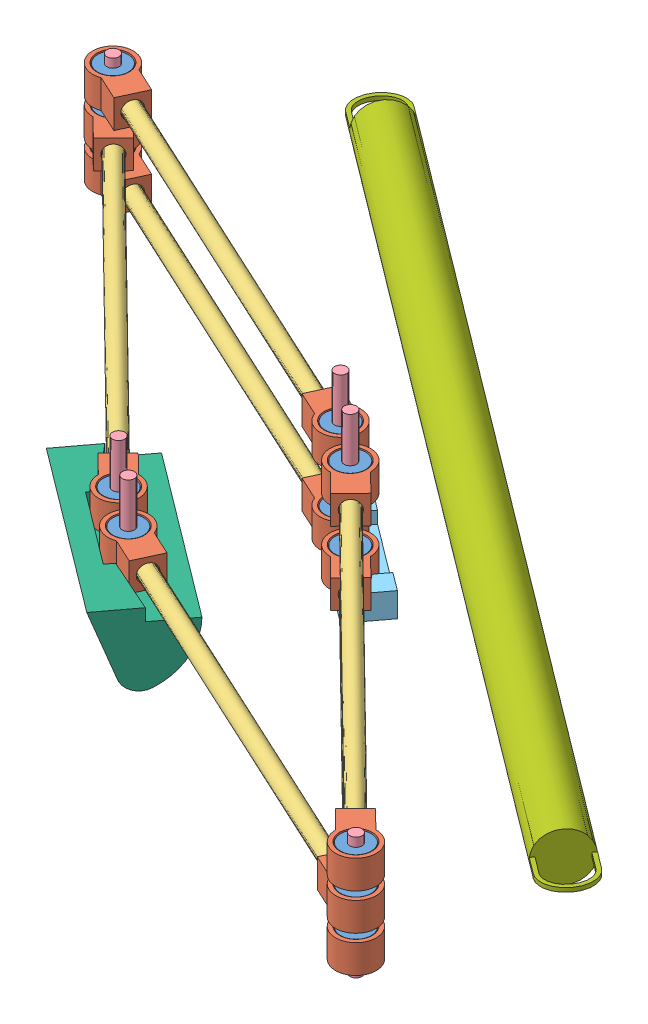
SolidWorks assembly leg_assembly1, configuration Default. Lengths in mm.
Overall size (234.39 41.67 185.98).
39 component instances, 7 part files, 94 mates.
Components (placement in the parent):
- bushing-3: bushing [Default] at (-50.3591 2.1821 -25.7812) x (0.792479 0 -0.609899) z (0.609899 0 0.792479) size (7.5 5 7.5)
- LegConnector1-3: LegConnector1 [Default] at (-50.3591 -3.9179 -25.7812) x (0.420255 0 -0.907406) z (0.907406 0 0.420255) size (10 7 15)
- bushing-4: bushing [Default] at (53.9926 2.1821 22.5482) size (7.5 5 7.5)
- LegCarbon-2: LegCarbon [Default] at (-45.8221 -0.4179 -23.6799) x (0.346449 0.566041 -0.748044) z (0.237882 -0.824377 -0.513629) size (4 105 4)
- LegConnector1-4: LegConnector1 [Default] at (53.9926 -3.9179 22.5482) x (-0.420255 0 0.907406) z (-0.907406 0 -0.420255) size (10 7 15)
- bushing-5: bushing [Default] at (-28.0167 11.1821 -58.0712) x (0.792479 0 -0.609899) z (0.609899 0 0.792479) size (7.5 5 7.5)
- LegConnector1-5: LegConnector1 [Default] at (-28.0167 5.0821 -58.0712) x (0.701038 0 -0.713124) z (0.713124 0 0.701038) size (10 7 15)
- bushing-6: bushing [Default] at (53.9926 11.1821 22.5482) size (7.5 5 7.5)
- LegCarbon-3: LegCarbon [Default] at (-24.4511 8.5821 -54.566) x (-0.676998 -0.259628 0.68867) z (-0.182009 0.965709 0.185147) size (4 105 4)
- LegConnector1-6: LegConnector1 [Default] at (53.9926 5.0821 22.5482) x (-0.701038 0 0.713124) z (-0.713124 0 -0.701038) size (10 7 15)
- bushing-7: bushing [Default] at (-28.0167 -6.8179 -58.0712) x (0.792479 0 -0.609899) z (0.609899 0 0.792479) size (7.5 5 7.5)
- LegConnector1-7: LegConnector1 [Default] at (-28.0167 -12.9179 -58.0712) x (0.701038 0 -0.713124) z (0.713124 0 0.701038) size (10 7 15)
- bushing-8: bushing [Default] at (53.9926 -6.8179 22.5482) size (7.5 5 7.5)
- LegCarbon-4: LegCarbon [Default] at (-24.4511 -9.4179 -54.566) x (0.513161 -0.681303 -0.522008) z (-0.477619 -0.732001 0.485854) size (4 105 4)
- LegConnector1-8: LegConnector1 [Default] at (53.9926 -12.9179 22.5482) x (-0.701038 0 0.713124) z (-0.713124 0 -0.701038) size (10 7 15)
- bushing-10: bushing [Default] at (-59.954 2.1821 -32.988) size (7.5 5 7.5)
- ScrewThread-1: ScrewThread [Default] at (53.9926 -15.9179 22.5482) x (0.842646 0 0.538468) z (-0.538468 0 0.842646) size (3 30 3)
- LegConnector1-11: LegConnector1 [Default] at (-59.954 -3.9179 -32.988) x (-0.701038 0 0.713124) z (-0.713124 0 -0.701038) size (10 7 15)
- LegCarbon-6: LegCarbon [Default] at (-42.1487 -9.4179 -67.3792) x (-0.307627 -0.681303 0.664222) z (0.286321 -0.732001 -0.618218) size (4 105 4)
- LegConnector1-12: LegConnector1 [Default] at (-141.9633 -12.9179 -113.6073) x (0.420255 0 -0.907406) z (0.907406 0 0.420255) size (10 7 15)
- ScrewThread-2: ScrewThread [Default] at (-141.9633 -15.9179 -113.6073) x (0.842646 0 0.538468) z (-0.538468 0 0.842646) size (3 30 3)
- bushing-11: bushing [Default] at (-141.9633 2.1821 -113.6073) size (7.5 5 7.5)
- LegConnector1-13: LegConnector1 [Default] at (-141.9633 -3.9179 -113.6073) x (0.701038 0 -0.713124) z (0.713124 0 0.701038) size (10 7 15)
- LegCarbon-7: LegCarbon [Default] at (-63.5196 -0.4179 -36.4932) x (-0.577919 0.566041 0.587883) z (-0.396816 -0.824377 0.403658) size (4 105 4)
- bushing-12: bushing [Default] at (-141.9633 -6.8179 -113.6073) size (7.5 5 7.5)
- LegCarbon-8: LegCarbon [Default] at (-42.1487 8.5821 -67.3792) x (0.405844 -0.259628 -0.87629) z (0.10911 0.965709 -0.235588) size (4 105 4)
- LegConnector1-14: LegConnector1 [Default] at (-141.9633 5.0821 -113.6073) x (0.420255 0 -0.907406) z (0.907406 0 0.420255) size (10 7 15)
- LegConnector1-15: LegConnector1 [Default] at (-37.6116 -12.9179 -65.278) x (-0.420255 0 0.907406) z (-0.907406 0 -0.420255) size (10 7 15)
- bushing-13: bushing [Default] at (-37.6116 -6.8179 -65.278) x (0.792479 0 -0.609899) z (0.609899 0 0.792479) size (7.5 5 7.5)
- bushing-14: bushing [Default] at (-141.9633 11.1821 -113.6073) size (7.5 5 7.5)
- bushing-15: bushing [Default] at (-37.6116 11.1821 -65.278) x (0.792479 0 -0.609899) z (0.609899 0 0.792479) size (7.5 5 7.5)
- LegConnector1-16: LegConnector1 [Default] at (-37.6116 5.0821 -65.278) x (-0.420255 0 0.907406) z (-0.907406 0 -0.420255) size (10 7 15)
- Bum2-2: Bum2 [Default] at (-22.6222 -16.1179 -50.2674) x (-0.799576 0 -0.600564) z (0.600564 0 -0.799576) size (30 9 10)
- Foot1-2: Foot1 [Default] at (-77.0435 -19.9118 -41.8724) x (0.600564 0 -0.799576) z (0 -1 0) size (20.25 50 17.67)
- ScrewThread-5: ScrewThread [Default] at (-50.3591 -16.1179 -25.7812) size (3 30 3)
- ScrewThread-6: ScrewThread [Default] at (-59.954 -16.1179 -32.988) size (3 30 3)
- ScrewThread-7: ScrewThread [Default] at (-28.0167 -7.1179 -58.0712) x (0.951589 0 0.307372) z (-0.307372 0 0.951589) size (3 30 3)
- ScrewThread-8: ScrewThread [Default] at (-37.6116 -7.1179 -65.278) size (3 30 3)
- Spring_ext-1: Spring_ext [Default] at (72.2619 1.5513 -10.2483) x (-0.424663 0.707107 0.565386) z (-0.424663 -0.707107 0.565386) size (12 242 12)
Mates (geometry in assembly coordinates):
- Concentric5: concentric anti-aligned: cylinder of bushing-4 through (53.9926 -2.0679 22.5482) axis (0 1 0) radius 2.25; cylinder of LegConnector1-4 through (53.9926 3.0821 22.5482) axis (0 -1 0) radius 2.45
- Concentric6: concentric anti-aligned: cylinder of bushing-3 through (-50.3591 -2.0679 -25.7812) axis (0 1 0) radius 2.25; cylinder of LegConnector1-3 through (-50.3591 3.0821 -25.7812) axis (0 -1 0) radius 2.45
- Concentric7: concentric anti-aligned: cylinder of LegCarbon-2 through (49.4555 -0.4179 20.4469) axis (-0.907406 0 -0.420255) radius 2; cylinder of LegConnector1-4 through (44.9185 -0.4179 18.3456) axis (0.907406 0 0.420255) radius 2.2
- Coincident7: coincident anti-aligned: plane of bushing-3 through (-50.3591 2.1821 -25.7812) normal (0 -1 0); plane of LegConnector1-3 through (-50.3591 2.1821 -25.7812) normal (0 1 0)
- Coincident8: coincident anti-aligned: plane of LegCarbon-2 through (49.4555 -0.4179 20.4469) normal (0.907406 0 0.420255); plane of LegConnector1-4 through (49.4555 -3.9179 20.4469) normal (-0.907406 0 -0.420255)
- Coincident9: coincident anti-aligned: plane of bushing-4 through (53.9926 2.1821 22.5482) normal (0 -1 0); plane of LegConnector1-4 through (53.9926 2.1821 22.5482) normal (0 1 0)
- Coincident10: coincident anti-aligned: plane of LegConnector1-3 through (-45.8221 -3.9179 -23.6799) normal (0.907406 0 0.420255); plane of LegCarbon-2 through (-45.8221 -0.4179 -23.6799) normal (-0.907406 0 -0.420255)
- Parallel3: parallel aligned: plane of LegConnector1-3 through (-45.7123 -3.9179 -27.4862) normal (0.420255 0 -0.907406); plane of LegConnector1-4 through (52.2875 -3.9179 17.9013) normal (0.420255 0 -0.907406)
- Parallel4: parallel aligned: plane of LegConnector1-3 through (-50.3591 3.0821 -25.7812) normal (0 1 0); plane of LegConnector1-4 through (53.9926 3.0821 22.5482) normal (0 1 0)
- Concentric8: concentric aligned: cylinder of LegConnector1-3 through (-41.2851 -0.4179 -21.5786) axis (-0.907406 0 -0.420255) radius 2.2; cylinder of LegCarbon-2 through (49.4555 -0.4179 20.4469) axis (-0.907406 0 -0.420255) radius 2
- Concentric9: concentric anti-aligned: cylinder of bushing-6 through (53.9926 6.9321 22.5482) axis (0 1 0) radius 2.25; cylinder of LegConnector1-6 through (53.9926 12.0821 22.5482) axis (0 -1 0) radius 2.45
- Concentric10: concentric anti-aligned: cylinder of bushing-5 through (-28.0167 6.9321 -58.0712) axis (0 1 0) radius 2.25; cylinder of LegConnector1-5 through (-28.0167 12.0821 -58.0712) axis (0 -1 0) radius 2.45
- Concentric11: concentric anti-aligned: cylinder of LegCarbon-3 through (50.427 8.5821 19.043) axis (-0.713124 0 -0.701038) radius 2; cylinder of LegConnector1-6 through (46.8613 8.5821 15.5378) axis (0.713124 0 0.701038) radius 2.2
- Coincident11: coincident anti-aligned: plane of bushing-5 through (-28.0167 11.1821 -58.0712) normal (0 -1 0); plane of LegConnector1-5 through (-28.0167 11.1821 -58.0712) normal (0 1 0)
- Coincident12: coincident anti-aligned: plane of LegCarbon-3 through (50.427 8.5821 19.043) normal (0.713124 0 0.701038); plane of LegConnector1-6 through (50.427 5.0821 19.043) normal (-0.713124 0 -0.701038)
- Coincident13: coincident anti-aligned: plane of bushing-6 through (53.9926 11.1821 22.5482) normal (0 -1 0); plane of LegConnector1-6 through (53.9926 11.1821 22.5482) normal (0 1 0)
- Coincident14: coincident anti-aligned: plane of LegConnector1-5 through (-24.4511 5.0821 -54.566) normal (0.713124 0 0.701038); plane of LegCarbon-3 through (-24.4511 8.5821 -54.566) normal (-0.713124 0 -0.701038)
- Parallel5: parallel aligned: plane of LegConnector1-5 through (-23.0671 5.0821 -58.1135) normal (0.701038 0 -0.713124); plane of LegConnector1-6 through (53.9503 5.0821 17.5986) normal (0.701038 0 -0.713124)
- Parallel6: parallel aligned: plane of LegConnector1-5 through (-28.0167 12.0821 -58.0712) normal (0 1 0); plane of LegConnector1-6 through (53.9926 12.0821 22.5482) normal (0 1 0)
- Concentric12: concentric aligned: cylinder of LegConnector1-5 through (-20.8855 8.5821 -51.0608) axis (-0.713124 0 -0.701038) radius 2.2; cylinder of LegCarbon-3 through (50.427 8.5821 19.043) axis (-0.713124 0 -0.701038) radius 2
- Concentric13: concentric anti-aligned: cylinder of bushing-8 through (53.9926 -11.0679 22.5482) axis (0 1 0) radius 2.25; cylinder of LegConnector1-8 through (53.9926 -5.9179 22.5482) axis (0 -1 0) radius 2.45
- Concentric14: concentric anti-aligned: cylinder of bushing-7 through (-28.0167 -11.0679 -58.0712) axis (0 1 0) radius 2.25; cylinder of LegConnector1-7 through (-28.0167 -5.9179 -58.0712) axis (0 -1 0) radius 2.45
- Concentric15: concentric anti-aligned: cylinder of LegCarbon-4 through (50.427 -9.4179 19.043) axis (-0.713124 0 -0.701038) radius 2; cylinder of LegConnector1-8 through (46.8613 -9.4179 15.5378) axis (0.713124 0 0.701038) radius 2.2
- Coincident15: coincident anti-aligned: plane of bushing-7 through (-28.0167 -6.8179 -58.0712) normal (0 -1 0); plane of LegConnector1-7 through (-28.0167 -6.8179 -58.0712) normal (0 1 0)
- Coincident16: coincident anti-aligned: plane of LegCarbon-4 through (50.427 -9.4179 19.043) normal (0.713124 0 0.701038); plane of LegConnector1-8 through (50.427 -12.9179 19.043) normal (-0.713124 0 -0.701038)
- Coincident17: coincident anti-aligned: plane of bushing-8 through (53.9926 -6.8179 22.5482) normal (0 -1 0); plane of LegConnector1-8 through (53.9926 -6.8179 22.5482) normal (0 1 0)
- Coincident18: coincident anti-aligned: plane of LegConnector1-7 through (-24.4511 -12.9179 -54.566) normal (0.713124 0 0.701038); plane of LegCarbon-4 through (-24.4511 -9.4179 -54.566) normal (-0.713124 0 -0.701038)
- Parallel7: parallel aligned: plane of LegConnector1-7 through (-23.0671 -12.9179 -58.1135) normal (0.701038 0 -0.713124); plane of LegConnector1-8 through (53.9503 -12.9179 17.5986) normal (0.701038 0 -0.713124)
- Parallel8: parallel aligned: plane of LegConnector1-7 through (-28.0167 -5.9179 -58.0712) normal (0 1 0); plane of LegConnector1-8 through (53.9926 -5.9179 22.5482) normal (0 1 0)
- Concentric16: concentric aligned: cylinder of LegConnector1-7 through (-20.8855 -9.4179 -51.0608) axis (-0.713124 0 -0.701038) radius 2.2; cylinder of LegCarbon-4 through (50.427 -9.4179 19.043) axis (-0.713124 0 -0.701038) radius 2
- Concentric23: concentric aligned: cylinder of bushing-4 through (53.9926 2.9321 22.5482) axis (0 -1 0) radius 1.5; cylinder of ScrewThread-1 through (53.9926 14.0821 22.5482) axis (0 -1 0) radius 1.5
- Concentric24: concentric aligned: cylinder of bushing-6 through (53.9926 11.9321 22.5482) axis (0 -1 0) radius 1.5; cylinder of ScrewThread-1 through (53.9926 14.0821 22.5482) axis (0 -1 0) radius 1.5
- Concentric25: concentric aligned: cylinder of bushing-8 through (53.9926 -6.0679 22.5482) axis (0 -1 0) radius 1.5; cylinder of ScrewThread-1 through (53.9926 14.0821 22.5482) axis (0 -1 0) radius 1.5
- Distance3: distance = 2 mm anti-aligned: plane of LegConnector1-4 through (53.9926 3.0821 22.5482) normal (0 1 0); plane of LegConnector1-6 through (53.9926 5.0821 22.5482) normal (0 -1 0)
- Distance4: distance = 2 mm anti-aligned: plane of LegConnector1-4 through (53.9926 -3.9179 22.5482) normal (0 -1 0); plane of LegConnector1-8 through (53.9926 -5.9179 22.5482) normal (0 1 0)
- Distance5: distance = 2 mm aligned: plane of LegConnector1-6 through (53.9926 12.0821 22.5482) normal (0 1 0); plane of ScrewThread-1 through (53.9926 14.0821 22.5482) normal (0 1 0)
- Parallel11: parallel aligned: line of LegConnector1-5 through (-23.0167 12.0821 -58.0639) axis (0.713124 0 0.701038); line of LegConnector1-7 through (-27.924 -5.9179 -53.0721) axis (0.713124 0 0.701038)
- Coincident31: coincident anti-aligned: plane of bushing-15 through (-37.6116 11.1821 -65.278) normal (0 -1 0); plane of LegConnector1-16 through (-37.6116 11.1821 -65.278) normal (0 1 0)
- Coincident32: coincident anti-aligned: plane of LegConnector1-14 through (-141.9633 11.1821 -113.6073) normal (0 1 0); plane of bushing-14 through (-141.9633 11.1821 -113.6073) normal (0 -1 0)
- Coincident33: coincident anti-aligned: plane of LegCarbon-8 through (-42.1487 8.5821 -67.3792) normal (0.907406 0 0.420255); plane of LegConnector1-16 through (-42.1487 5.0821 -67.3792) normal (-0.907406 0 -0.420255)
- Parallel12: parallel aligned: plane of LegConnector1-14 through (-141.9633 12.0821 -113.6073) normal (0 1 0); plane of LegConnector1-16 through (-37.6116 12.0821 -65.278) normal (0 1 0)
- Coincident34: coincident anti-aligned: plane of LegCarbon-8 through (-137.4263 8.5821 -111.506) normal (-0.907406 0 -0.420255); plane of LegConnector1-14 through (-137.4263 5.0821 -111.506) normal (0.907406 0 0.420255)
- Parallel13: parallel aligned: plane of LegConnector1-14 through (-140.2583 5.0821 -108.9605) normal (-0.420255 0 0.907406); plane of LegConnector1-16 through (-42.2584 5.0821 -63.5729) normal (-0.420255 0 0.907406)
- Coincident35: coincident anti-aligned: plane of LegCarbon-6 through (-42.1487 -9.4179 -67.3792) normal (0.907406 0 0.420255); plane of LegConnector1-15 through (-42.1487 -12.9179 -67.3792) normal (-0.907406 0 -0.420255)
- Coincident36: coincident anti-aligned: plane of LegConnector1-13 through (-138.3977 -3.9179 -110.1021) normal (0.713124 0 0.701038); plane of LegCarbon-7 through (-138.3977 -0.4179 -110.1021) normal (-0.713124 0 -0.701038)
- Coincident37: coincident anti-aligned: plane of LegConnector1-11 through (-63.5196 -3.9179 -36.4932) normal (-0.713124 0 -0.701038); plane of LegCarbon-7 through (-63.5196 -0.4179 -36.4932) normal (0.713124 0 0.701038)
- Coincident38: coincident anti-aligned: plane of LegConnector1-15 through (-37.6116 -6.8179 -65.278) normal (0 1 0); plane of bushing-13 through (-37.6116 -6.8179 -65.278) normal (0 -1 0)
- Parallel14: parallel aligned: plane of LegConnector1-11 through (-59.954 3.0821 -32.988) normal (0 1 0); plane of LegConnector1-13 through (-141.9633 3.0821 -113.6073) normal (0 1 0)
- Coincident39: coincident anti-aligned: plane of LegConnector1-12 through (-141.9633 -6.8179 -113.6073) normal (0 1 0); plane of bushing-12 through (-141.9633 -6.8179 -113.6073) normal (0 -1 0)
- Parallel15: parallel aligned: plane of LegConnector1-11 through (-64.9036 -3.9179 -32.9457) normal (-0.701038 0 0.713124); plane of LegConnector1-13 through (-141.921 -3.9179 -108.6577) normal (-0.701038 0 0.713124)
- Parallel16: parallel aligned: plane of LegConnector1-12 through (-140.2583 -12.9179 -108.9605) normal (-0.420255 0 0.907406); plane of LegConnector1-15 through (-42.2584 -12.9179 -63.5729) normal (-0.420255 0 0.907406)
- Parallel17: parallel aligned: plane of LegConnector1-12 through (-141.9633 -5.9179 -113.6073) normal (0 1 0); plane of LegConnector1-15 through (-37.6116 -5.9179 -65.278) normal (0 1 0)
- Coincident40: coincident anti-aligned: plane of bushing-11 through (-141.9633 2.1821 -113.6073) normal (0 -1 0); plane of LegConnector1-13 through (-141.9633 2.1821 -113.6073) normal (0 1 0)
- Coincident41: coincident anti-aligned: plane of LegCarbon-6 through (-137.4263 -9.4179 -111.506) normal (-0.907406 0 -0.420255); plane of LegConnector1-12 through (-137.4263 -12.9179 -111.506) normal (0.907406 0 0.420255)
- Concentric26: concentric anti-aligned: cylinder of LegConnector1-15 through (-37.6116 -5.9179 -65.278) axis (0 -1 0) radius 2.45; cylinder of bushing-13 through (-37.6116 -11.0679 -65.278) axis (0 1 0) radius 2.25
- Concentric27: concentric aligned: cylinder of LegCarbon-6 through (-137.4263 -9.4179 -111.506) axis (0.907406 0 0.420255) radius 2; cylinder of LegConnector1-15 through (-46.6857 -9.4179 -69.4805) axis (0.907406 0 0.420255) radius 2.2
- Concentric28: concentric anti-aligned: cylinder of LegCarbon-6 through (-137.4263 -9.4179 -111.506) axis (0.907406 0 0.420255) radius 2; cylinder of LegConnector1-12 through (-132.8892 -9.4179 -109.4048) axis (-0.907406 0 -0.420255) radius 2.2
- Concentric29: concentric aligned: cylinder of ScrewThread-2 through (-141.9633 14.0821 -113.6073) axis (0 -1 0) radius 1.5; cylinder of bushing-12 through (-141.9633 -6.0679 -113.6073) axis (0 -1 0) radius 1.5
- Distance6: distance = 2 mm anti-aligned: plane of LegConnector1-13 through (-141.9633 3.0821 -113.6073) normal (0 1 0); plane of LegConnector1-14 through (-141.9633 5.0821 -113.6073) normal (0 -1 0)
- Parallel18: parallel aligned: line of LegConnector1-15 through (-39.3808 -5.9179 -69.9545) axis (-0.907406 0 -0.420255); line of LegConnector1-16 through (-42.3226 12.0821 -63.6027) axis (-0.907406 0 -0.420255)
- Concentric30: concentric anti-aligned: cylinder of LegConnector1-14 through (-141.9633 12.0821 -113.6073) axis (0 -1 0) radius 2.45; cylinder of bushing-14 through (-141.9633 6.9321 -113.6073) axis (0 1 0) radius 2.25
- Concentric31: concentric anti-aligned: cylinder of bushing-11 through (-141.9633 -2.0679 -113.6073) axis (0 1 0) radius 2.25; cylinder of LegConnector1-13 through (-141.9633 3.0821 -113.6073) axis (0 -1 0) radius 2.45
- Concentric32: concentric anti-aligned: cylinder of LegConnector1-13 through (-134.8321 -0.4179 -106.5969) axis (-0.713124 0 -0.701038) radius 2.2; cylinder of LegCarbon-7 through (-138.3977 -0.4179 -110.1021) axis (0.713124 0 0.701038) radius 2
- Concentric33: concentric aligned: cylinder of LegConnector1-11 through (-67.0853 -0.4179 -39.9983) axis (0.713124 0 0.701038) radius 2.2; cylinder of LegCarbon-7 through (-138.3977 -0.4179 -110.1021) axis (0.713124 0 0.701038) radius 2
- Concentric34: concentric anti-aligned: cylinder of LegCarbon-8 through (-137.4263 8.5821 -111.506) axis (0.907406 0 0.420255) radius 2; cylinder of LegConnector1-14 through (-132.8892 8.5821 -109.4048) axis (-0.907406 0 -0.420255) radius 2.2
- Concentric35: concentric anti-aligned: cylinder of bushing-15 through (-37.6116 6.9321 -65.278) axis (0 1 0) radius 2.25; cylinder of LegConnector1-16 through (-37.6116 12.0821 -65.278) axis (0 -1 0) radius 2.45
- Concentric36: concentric aligned: cylinder of LegCarbon-8 through (-137.4263 8.5821 -111.506) axis (0.907406 0 0.420255) radius 2; cylinder of LegConnector1-16 through (-46.6857 8.5821 -69.4805) axis (0.907406 0 0.420255) radius 2.2
- Distance7: distance = 2 mm aligned: plane of LegConnector1-14 through (-141.9633 12.0821 -113.6073) normal (0 1 0); plane of ScrewThread-2 through (-141.9633 14.0821 -113.6073) normal (0 1 0)
- Concentric37: concentric anti-aligned: cylinder of LegConnector1-12 through (-141.9633 -5.9179 -113.6073) axis (0 -1 0) radius 2.45; cylinder of bushing-12 through (-141.9633 -11.0679 -113.6073) axis (0 1 0) radius 2.25
- Concentric38: concentric aligned: cylinder of ScrewThread-2 through (-141.9633 14.0821 -113.6073) axis (0 -1 0) radius 1.5; cylinder of bushing-11 through (-141.9633 2.9321 -113.6073) axis (0 -1 0) radius 1.5
- Distance9: distance = 2 mm anti-aligned: plane of LegConnector1-13 through (-141.9633 -3.9179 -113.6073) normal (0 -1 0); plane of LegConnector1-12 through (-141.9633 -5.9179 -113.6073) normal (0 1 0)
- Concentric39: concentric aligned: cylinder of ScrewThread-2 through (-141.9633 14.0821 -113.6073) axis (0 -1 0) radius 1.5; cylinder of bushing-14 through (-141.9633 11.9321 -113.6073) axis (0 -1 0) radius 1.5
- Concentric40: concentric aligned: cylinder of bushing-10 through (-59.954 2.9321 -32.988) axis (0 -1 0) radius 1.5; cylinder of LegConnector1-11 through (-59.954 3.0821 -32.988) axis (0 -1 0) radius 2.45
- Coincident42: coincident anti-aligned: plane of bushing-10 through (-59.954 2.1821 -32.988) normal (0 -1 0); plane of LegConnector1-11 through (-59.954 2.1821 -32.988) normal (0 1 0)
- Concentric41: concentric anti-aligned: cylinder of bushing-15 through (-37.6116 11.9321 -65.278) axis (0 -1 0) radius 1.5; cylinder of Bum2-2 through (-37.6116 -13.1179 -65.278) axis (0 1 0) radius 1.5
- Distance10: distance = 0.2 mm anti-aligned: plane of Bum2-2 through (-22.6222 -13.1179 -50.2674) normal (0 1 0); plane of LegConnector1-15 through (-37.6116 -12.9179 -65.278) normal (0 -1 0)
- Concentric42: concentric anti-aligned: cylinder of bushing-7 through (-28.0167 -6.0679 -58.0712) axis (0 -1 0) radius 1.5; cylinder of Bum2-2 through (-28.0167 -13.1179 -58.0712) axis (0 1 0) radius 1.5
- Concentric43: concentric anti-aligned: cylinder of Foot1-2 through (-59.954 -16.1179 -32.988) axis (0 1 0) radius 1.6; cylinder of ScrewThread-6 through (-59.954 13.8821 -32.988) axis (0 -1 0) radius 1.5
- Concentric44: concentric anti-aligned: cylinder of Foot1-2 through (-50.3591 -16.1179 -25.7812) axis (0 1 0) radius 1.6; cylinder of ScrewThread-5 through (-50.3591 13.8821 -25.7812) axis (0 -1 0) radius 1.5
- Coincident44: coincident anti-aligned: plane of Foot1-2 through (-59.954 -16.1179 -32.988) normal (0 1 0); plane of ScrewThread-6 through (-59.954 -16.1179 -32.988) normal (0 -1 0)
- Coincident45: coincident anti-aligned: plane of Foot1-2 through (-50.3591 -16.1179 -25.7812) normal (0 1 0); plane of ScrewThread-5 through (-50.3591 -16.1179 -25.7812) normal (0 -1 0)
- Concentric45: concentric aligned: cylinder of bushing-10 through (-59.954 2.9321 -32.988) axis (0 -1 0) radius 1.5; cylinder of ScrewThread-6 through (-59.954 13.8821 -32.988) axis (0 -1 0) radius 1.5
- Concentric46: concentric aligned: cylinder of bushing-3 through (-50.3591 2.9321 -25.7812) axis (0 -1 0) radius 1.5; cylinder of ScrewThread-5 through (-50.3591 13.8821 -25.7812) axis (0 -1 0) radius 1.5
- Distance11: distance = 0.2 mm anti-aligned: plane of LegConnector1-3 through (-50.3591 -3.9179 -25.7812) normal (0 -1 0); plane of Foot1-2 through (-77.0435 -4.1179 -41.8724) normal (0 1 0)
- Parallel19: parallel aligned: line of Bum2-2 through (-21.0177 -13.1179 -61.5688) axis (-0.799576 0 -0.600564); line of Foot1-2 through (-29.0141 -4.1179 -22.5625) axis (-0.799576 0 -0.600564)
- LimitAngle1: limit planar angle = 1.438151 rad aligned: line of LegConnector1-13 through (-141.8706 3.0821 -108.6082) axis (0.713124 0 0.701038); line of Foot1-2 through (-68.9929 -4.1179 -52.5907) axis (-0.600564 0 0.799576)
- Distance14: distance = 0.2 mm anti-aligned: plane of LegConnector1-7 through (-28.0167 -12.9179 -58.0712) normal (0 -1 0); plane of Bum2-2 through (-22.6222 -13.1179 -50.2674) normal (0 1 0)
- LimitAngle2: limit planar angle = 1.360316 rad anti-aligned: line of LegConnector1-4 through (49.2816 3.0821 24.2235) axis (-0.907406 0 -0.420255); line of Foot1-2 through (-34.9982 -4.1179 -14.5954) axis (0.600564 0 -0.799576)
- Coincident54: coincident anti-aligned: plane of Bum2-2 through (-22.6222 -7.1179 -50.2674) normal (0 1 0); plane of ScrewThread-7 through (-28.0167 -7.1179 -58.0712) normal (0 -1 0)
- Concentric47: concentric aligned: cylinder of bushing-5 through (-28.0167 11.9321 -58.0712) axis (0 -1 0) radius 1.5; cylinder of ScrewThread-7 through (-28.0167 22.8821 -58.0712) axis (0 -1 0) radius 1.5
- Coincident55: coincident anti-aligned: plane of Bum2-2 through (-22.6222 -7.1179 -50.2674) normal (0 1 0); plane of ScrewThread-8 through (-37.6116 -7.1179 -65.278) normal (0 -1 0)
- Concentric48: concentric aligned: cylinder of bushing-13 through (-37.6116 -6.0679 -65.278) axis (0 -1 0) radius 1.5; cylinder of ScrewThread-8 through (-37.6116 22.8821 -65.278) axis (0 -1 0) radius 1.5
- Parallel22: parallel anti-aligned: cylinder of ScrewThread-2 through (-141.9633 14.0821 -113.6073) axis (0 -1 0) radius 1.5; face of Spring_ext-1
- Parallel23: parallel aligned: line of Foot1-2 through (-41.1728 -1.1179 -6.3747) axis (-0.799576 0 -0.600564); line of Spring_ext-1 through (-108.8475 2.0513 -138.7761) axis (-0.799576 0 -0.600564)
